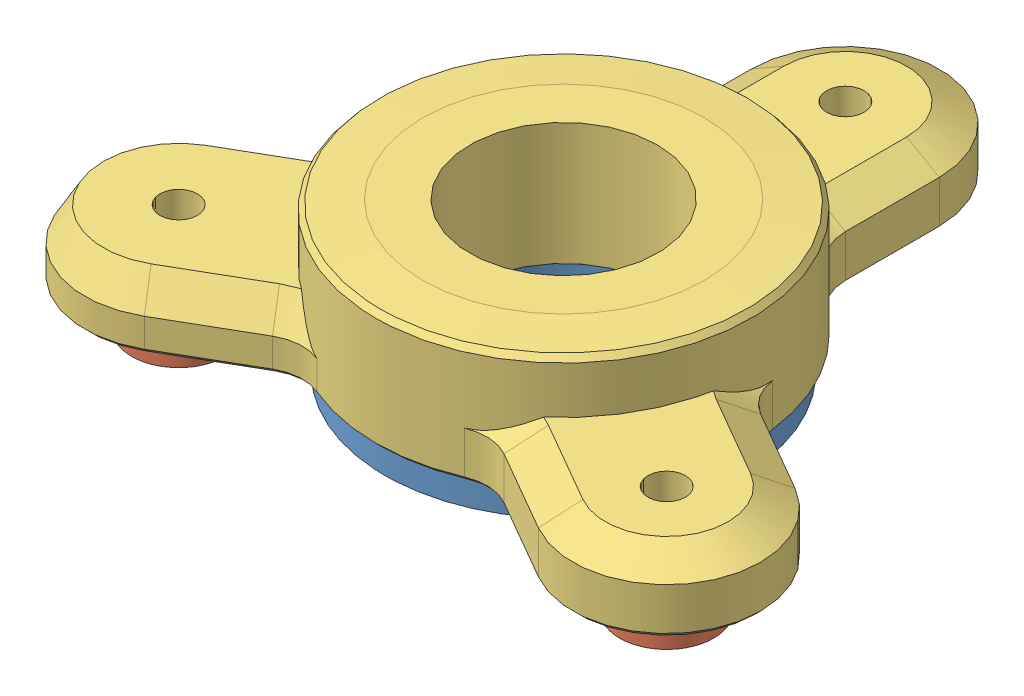
SolidWorks assembly slider_plate_bottom, configuration ﾃﾞﾌｫﾙﾄ. Lengths in mm.
Overall size (71.96 17.5 65).
5 component instances, 3 part files, 16 mates.
Components (placement in the parent):
- slider_plate_bottom_2-1: slider_plate_bottom_2 [ﾃﾞﾌｫﾙﾄ] at (12.1209 -9.7674 58.0801) size (38 3 38)
- slider_plate_bottom_pin-2: slider_plate_bottom_pin [ﾃﾞﾌｫﾙﾄ] at (38.1017 -11.2674 73.0801) size (10 4.5 10)
- slider_plate_bottom_pin-3: slider_plate_bottom_pin [ﾃﾞﾌｫﾙﾄ] at (-13.8599 -11.2674 73.0801) size (10 4.5 10)
- slider_plate_bottom_pin-4: slider_plate_bottom_pin [ﾃﾞﾌｫﾙﾄ] at (12.1209 -11.2674 28.0801) size (10 4.5 10)
- slider_plate_bottom_fixed-1: slider_plate_bottom_fixed [ﾃﾞﾌｫﾙﾄ] at (12.1209 -6.7674 58.0801) size (71.96 13 65)
Mates (geometry in assembly coordinates):
- 一致1: coincident anti-aligned: circle of ?; circle of slider_plate_bottom_2-1
- 同心円1: concentric anti-aligned: circle of ?; circle of slider_plate_bottom_pin-2
- 同心円2: concentric anti-aligned: circle of ?; circle of slider_plate_bottom_pin-3
- 一致2: coincident anti-aligned: plane of ? through (1.1128 -6.1551 69.0249) normal (0 -1 0); circle of slider_plate_bottom_pin-2
- 一致3: coincident anti-aligned: plane of ? through (1.1128 -6.1551 69.0249) normal (0 -1 0); plane of slider_plate_bottom_pin-3 through (-24.3151 -6.1551 84.9859) normal (0 1 0)
- 一致4: coincident anti-aligned: plane of ? through (1.1128 -6.1551 69.0249) normal (0 -1 0); circle of slider_plate_bottom_2-1
- 同心円3: concentric anti-aligned: circle of ?; circle of slider_plate_bottom_pin-4
- 一致5: coincident anti-aligned: plane of ? through (1.1128 -6.1551 69.0249) normal (0 -1 0); plane of slider_plate_bottom_pin-4 through (0.004 -6.1551 39.0231) normal (0 1 0)
- 一致6: coincident: plane of slider_plate_bottom_2-1 through (12.1209 -6.7674 58.0801) normal (0 1 0); plane of slider_plate_bottom_fixed-1 through (12.1209 -6.7674 58.0801) normal (0 -1 0)
- 一致7: coincident: plane of slider_plate_bottom_pin-4 through (12.1209 -6.7674 28.0801) normal (0 1 0); plane of slider_plate_bottom_fixed-1 through (12.1209 -6.7674 58.0801) normal (0 -1 0)
- 一致8: coincident: plane of slider_plate_bottom_pin-3 through (-13.8599 -6.7674 73.0801) normal (0 1 0); plane of slider_plate_bottom_fixed-1 through (12.1209 -6.7674 58.0801) normal (0 -1 0)
- 一致9: coincident: plane of slider_plate_bottom_pin-2 through (38.1017 -6.7674 73.0801) normal (0 1 0); plane of slider_plate_bottom_fixed-1 through (12.1209 -6.7674 58.0801) normal (0 -1 0)
- 同心円5: concentric anti-aligned: cylinder of slider_plate_bottom_2-1 through (12.1209 -9.7684 58.0801) axis (0 1 0) radius 10; cylinder of slider_plate_bottom_fixed-1 through (12.1209 6.2326 58.0801) axis (0 -1 0) radius 10
- 同心円6: concentric aligned: cylinder of slider_plate_bottom_pin-3 through (-13.8599 -6.7674 73.0801) axis (0 -1 0) radius 5; cylinder of slider_plate_bottom_fixed-1 through (-13.8599 0.2326 73.0801) axis (0 -1 0) radius 2
- 同心円7: concentric aligned: cylinder of slider_plate_bottom_pin-2 through (38.1017 -6.7674 73.0801) axis (0 -1 0) radius 5; cylinder of slider_plate_bottom_fixed-1 through (38.1017 0.2326 73.0801) axis (0 -1 0) radius 2
- 同心円8: concentric aligned: cylinder of slider_plate_bottom_pin-4 through (12.1209 -6.7674 28.0801) axis (0 -1 0) radius 5; cylinder of slider_plate_bottom_fixed-1 through (12.1209 0.2326 28.0801) axis (0 -1 0) radius 2
